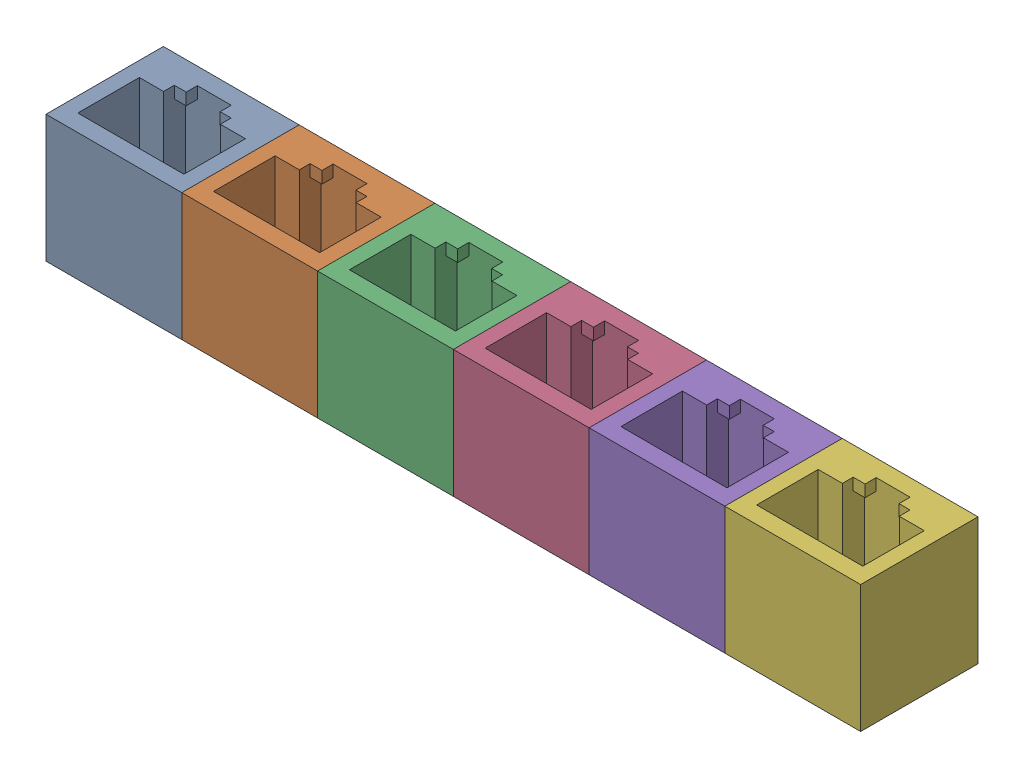
SolidWorks assembly 6-port block, configuration Default. Lengths in mm.
Overall size (96 15 13.83).
6 component instances, 1 part files, 15 mates.
Components (placement in the parent):
- RJ45 dummy jack trimmed-1: RJ45 dummy jack trimmed [Default] at (-42.6786 6.807 34.1283) size (16 15 13.83)
- RJ45 dummy jack trimmed-2: RJ45 dummy jack trimmed [Default] at (-26.6786 6.807 34.1283) size (16 15 13.83)
- RJ45 dummy jack trimmed-3: RJ45 dummy jack trimmed [Default] at (-10.6786 6.807 34.1283) size (16 15 13.83)
- RJ45 dummy jack trimmed-4: RJ45 dummy jack trimmed [Default] at (5.3214 6.807 34.1283) size (16 15 13.83)
- RJ45 dummy jack trimmed-5: RJ45 dummy jack trimmed [Default] at (21.3214 6.807 34.1283) size (16 15 13.83)
- RJ45 dummy jack trimmed-6: RJ45 dummy jack trimmed [Default] at (37.3214 6.807 34.1283) size (16 15 13.83)
Mates (geometry in assembly coordinates):
- Coincident1: coincident: plane of RJ45 dummy jack trimmed-1 through (-28.4286 31.807 22.2983) normal (1 0 0); plane of RJ45 dummy jack trimmed-2 through (-28.4286 31.807 22.2983) normal (-1 0 0)
- Coincident2: coincident: point of assembly; point of assembly; moEndPointRef_w of RJ45 dummy jack trimmed-1; moEndPointRef_w of RJ45 dummy jack trimmed-2
- Coincident3: coincident: unknown of RJ45 dummy jack trimmed-1; unknown of RJ45 dummy jack trimmed-2
- Coincident4: coincident: plane of RJ45 dummy jack trimmed-2 through (-12.4286 31.807 22.2983) normal (1 0 0); plane of RJ45 dummy jack trimmed-3 through (-12.4286 31.807 22.2983) normal (-1 0 0)
- Coincident5: coincident: point of assembly; point of assembly; moEndPointRef_w of RJ45 dummy jack trimmed-2; moEndPointRef_w of RJ45 dummy jack trimmed-3
- Coincident6: coincident: unknown of RJ45 dummy jack trimmed-2; unknown of RJ45 dummy jack trimmed-3
- Coincident7: coincident: plane of RJ45 dummy jack trimmed-3 through (3.5714 31.807 22.2983) normal (1 0 0); plane of RJ45 dummy jack trimmed-4 through (3.5714 31.807 22.2983) normal (-1 0 0)
- Coincident8: coincident: point of assembly; point of assembly; moEndPointRef_w of RJ45 dummy jack trimmed-3; moEndPointRef_w of RJ45 dummy jack trimmed-4
- Coincident9: coincident: unknown of RJ45 dummy jack trimmed-3; unknown of RJ45 dummy jack trimmed-4
- Coincident10: coincident: plane of RJ45 dummy jack trimmed-4 through (19.5714 31.807 22.2983) normal (1 0 0); plane of RJ45 dummy jack trimmed-5 through (19.5714 31.807 22.2983) normal (-1 0 0)
- Coincident11: coincident: point of assembly; point of assembly; moEndPointRef_w of RJ45 dummy jack trimmed-4; moEndPointRef_w of RJ45 dummy jack trimmed-5
- Coincident12: coincident: unknown of RJ45 dummy jack trimmed-4; unknown of RJ45 dummy jack trimmed-5
- Coincident13: coincident: plane of RJ45 dummy jack trimmed-5 through (35.5714 31.807 22.2983) normal (1 0 0); plane of RJ45 dummy jack trimmed-6 through (35.5714 31.807 22.2983) normal (-1 0 0)
- Coincident14: coincident: point of assembly; point of assembly; moEndPointRef_w of RJ45 dummy jack trimmed-5; moEndPointRef_w of RJ45 dummy jack trimmed-6
- Coincident15: coincident: unknown of RJ45 dummy jack trimmed-5; unknown of RJ45 dummy jack trimmed-6
